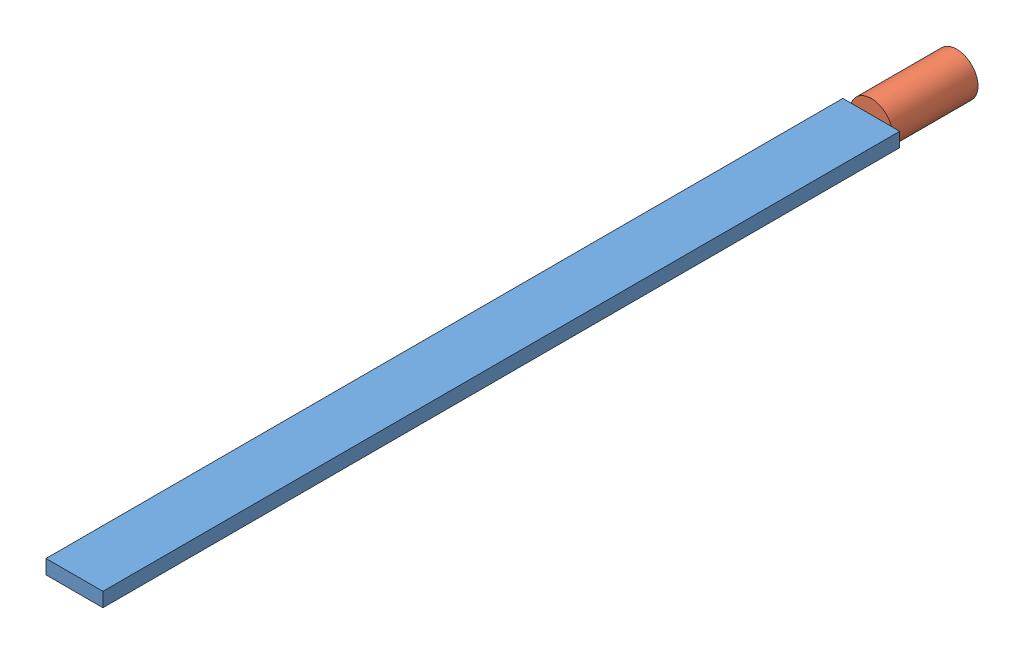
SolidWorks assembly 01-094-00-0, configuration Default. Lengths in mm.
Overall size (26.02 26.02 393.7).
2 component instances, 2 part files, 3 mates.
Components (placement in the parent):
- 01-093-00-0-1: 01-093-00-0 [Default] at (-45.5164 -22.3944 39.2328) size (25.4 6.35 355.6)
- TROD 0.7500-1x1.25-1: TROD 0.7500-1x1.25 [Default] at (-32.8164 -19.2194 -316.3672) x (0.5 -0.866025 0) z (0.866025 0.5 0) size (19.05 38.1 19.05)
Mates (geometry in assembly coordinates):
- Coincident1: coincident anti-aligned: plane of 01-093-00-0-1 through (-45.5164 -16.0444 -316.3672) normal (0 0 -1); plane of TROD 0.7500-1x1.25-1 through (-32.8164 -19.2194 -316.3672) normal (0 0 1)
- Distance1: distance = 3.175 mm: plane of 01-093-00-0-1 through (-45.5164 -16.0444 -316.3672) normal (0 1 0); moEndPointRef_w of TROD 0.7500-1x1.25-1
- Distance2: distance = 12.7 mm: plane of 01-093-00-0-1 through (-20.1164 -16.0444 39.2328) normal (1 0 0); moEndPointRef_w of TROD 0.7500-1x1.25-1
